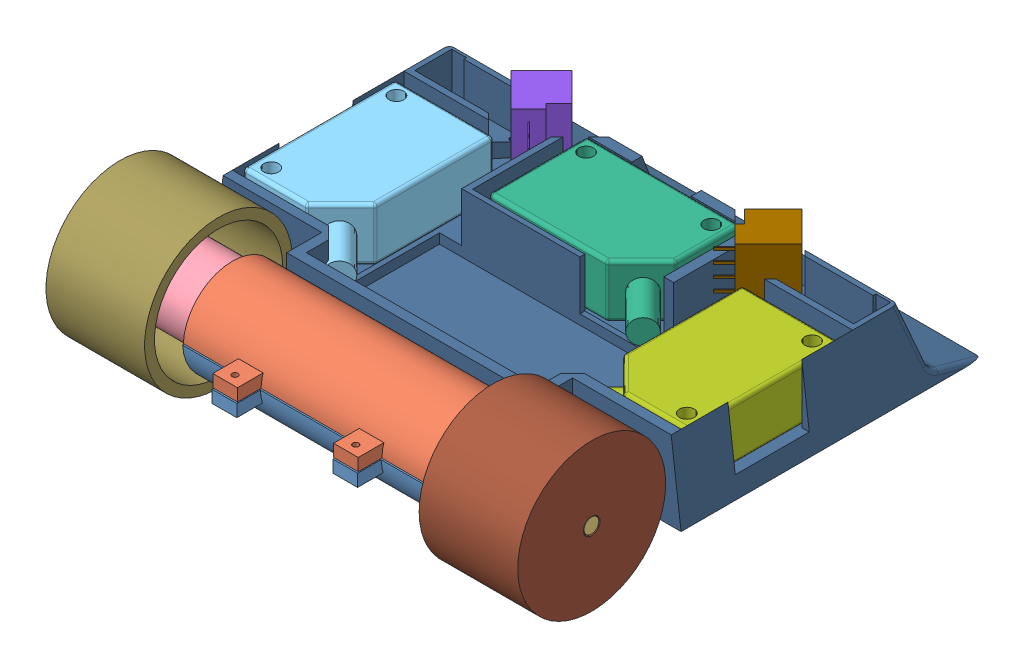
SolidWorks assembly Assem3, configuration Default. Lengths in mm.
Overall size (96.48 30.58 94.68).
12 component instances, 12 part files, 0 mates.
Components (placement in the parent):
- arka alt-1: arka alt [Default] at (-88.3935 43.8234 -22.4318) size (51 9.5 24.75)
- arka üst-1: arka üst [Default] at (-88.2888 43.1282 -22.4604) size (51 9.5 24.74)
- faullhabber-1: faullhabber [Default] at (-67.5582 24.5459 -53.9011) size (47.5 15 15)
- faullhabber - Copy-1: faullhabber - Copy [Default] at (-58.1158 25.1207 16.9682) x (-1 0 0) z (0 0 -1) size (47.5 15 15)
- omron4-1: omron4 [Default] at (-98.1381 49.8885 -55.9092) x (0 0 1) z (1 0 0) size (37.72 10.8 25.16)
- omron4 - Copy-1: omron4 - Copy [Default] at (-63.108 39.2325 -70.75) size (37.72 10.8 25.16)
- omron5-1: omron5 [Default] at (-27.783 38.1721 -55.863) x (0 0 1) z (-1 0 0) size (37.72 10.8 25.16)
- sharp - Copy-1: sharp - Copy [Default] at (-72.3093 48.1287 -71.3701) x (0.707107 0 0.707107) z (0 -1 0) size (12.7 8.7 15)
- sharp - Copy - Copy-1: sharp - Copy - Copy [Default] at (-53.3548 46.7455 -70.3044) x (-0.707107 0 0.707107) z (0 1 0) size (12.7 8.7 15)
- sharplı ön-1: sharplı ön [Default] at (-50.1396 34.9891 -28.7944) x (0 0 -1) z (1 0 0) size (68 16 95)
- tekerlek-1: tekerlek [Default] at (-34.9982 44.6046 -18.0801) size (20 30 30)
- tekerlek2-1: tekerlek2 [Default] at (-91.4738 45.1864 -18.8689) x (-1 0 0) z (0 0 -1) size (20 30 30)
